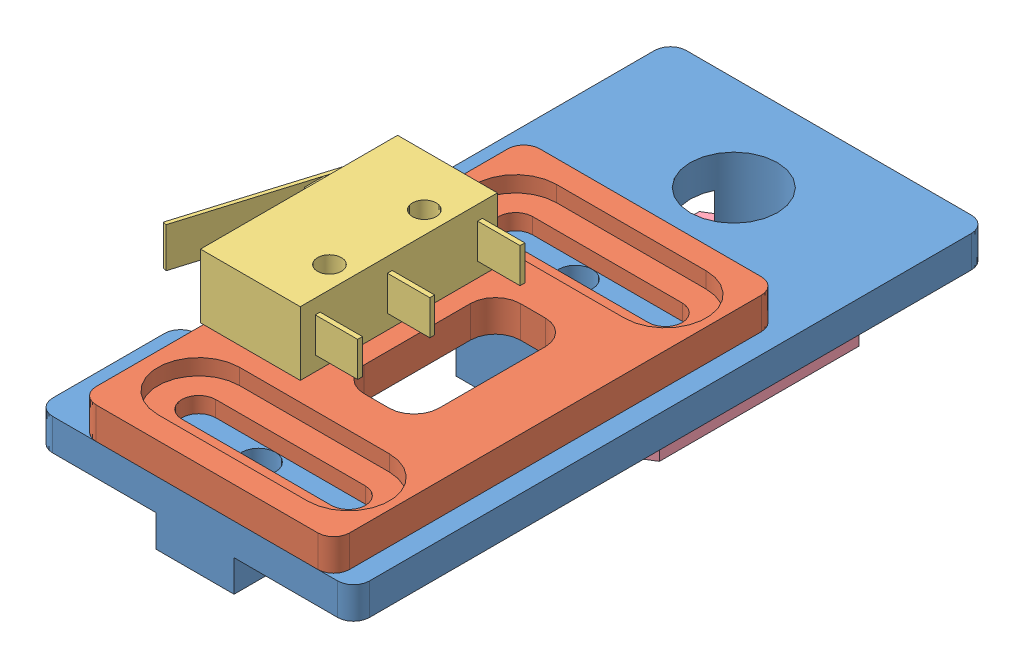
SolidWorks assembly Frame Carriage Endstop Assembly RH, configuration Default. Lengths in mm.
Overall size (33.09 22.27 63.5).
5 component instances, 5 part files, 15 mates.
Components (placement in the parent):
- Carriage Axis Endstop Mount Base RH-1: Carriage Axis Endstop Mount Base RH [Default] at (-146.9546 69.2713 -55.6911) size (31.75 6.35 63.5)
- Carriage Axis Endstop Mount Slide RH-1: Carriage Axis Endstop Mount Slide RH [Default] at (-148.9445 72.4463 7.8089) size (25.4 3.17 44.45)
- Endstop-4: Endstop [Default] at (-164.6445 75.6213 -4.5411) x (0 0 -1) z (1 0 0) size (19.75 6.4 19.65)
- 5_16in T-Slot Nut-1: 5_16in T-Slot Nut [Default] at (-170.8296 60.4163 -50.7161) x (0 0 1) z (-1 0 0) size (25 5.68 16)
- 5_16in x 0.5in T-Slot Bolt-1: 5_16in x 0.5in T-Slot Bolt [Default] at (-162.8296 59.7463 -46.1661) x (0 0 -1) z (1 0 0) size (16.95 16.6 16.95)
Mates (geometry in assembly coordinates):
- Tangent2: tangent: cylinder of ? through (16.9117 26.5861 68.4807) axis (0 1 0) radius 1.7; plane of ? through (9.8098 36.1111 66.7807) normal (0 0 1)
- Coincident1: coincident: plane of ? through (1.0367 32.9361 74.8307) normal (0 1 0); plane of ? through (4.9348 32.9361 74.8307) normal (0 -1 0)
- Coincident2: coincident: plane of ? through (1.0367 29.7611 74.8307) normal (0 0 1); plane of ? through (4.9348 36.1111 74.8307) normal (0 0 1)
- Coincident3: coincident: plane of ? through (4.9348 36.1111 74.8307) normal (0 1 0); plane of ? through (20.6348 36.1111 62.4807) normal (0 -1 0)
- Concentric1: concentric: cylinder of ? through (22.8348 36.1111 57.3557) axis (0 -1 0) radius 1.2; cylinder of ? through (22.8348 36.1111 57.3557) axis (0 1 0) radius 1.2
- Coincident5: coincident: plane of Carriage Axis Endstop Mount Slide RH-1 through (-148.9445 75.6213 7.8089) normal (0 1 0); plane of Endstop-4 through (-164.6445 75.6213 -4.5411) normal (0 -1 0)
- Concentric2: concentric: cylinder of Carriage Axis Endstop Mount Slide RH-1 through (-166.8445 75.6213 -19.1661) axis (0 -1 0) radius 1.2; cylinder of Endstop-4 through (-166.8445 82.0213 -19.1661) axis (0 -1 0) radius 1.2
- Concentric3: concentric: cylinder of Carriage Axis Endstop Mount Slide RH-1 through (-166.8445 75.6213 -9.6661) axis (0 -1 0) radius 1.2; cylinder of Endstop-4 through (-166.8445 82.0213 -9.6661) axis (0 -1 0) radius 1.2
- Concentric4: concentric: cylinder of Carriage Axis Endstop Mount Base RH-1 through (-162.8296 66.0963 -46.1661) axis (0 1 0) radius 4.3656; cylinder of ? through (-162.8296 72.4463 -46.1661) axis (0 -1 0) radius 3.9688
- Coincident6: coincident: plane of Carriage Axis Endstop Mount Base RH-1 through (-146.9546 72.4463 7.8089) normal (0 1 0); plane of ? through (-162.8296 72.4463 -46.1661) normal (0 -1 0)
- Concentric5: concentric: cylinder of ? through (-162.8296 72.4463 -46.1661) axis (0 -1 0) radius 3.9688; cylinder of 5_16in T-Slot Nut-1 through (-162.8296 64.0963 -46.1661) axis (0 -1 0) radius 3.9688
- Coincident8: coincident: plane of Carriage Axis Endstop Mount Base RH-1 through (-146.9546 66.0963 7.8089) normal (0 -1 0); plane of 5_16in T-Slot Nut-1 through (-162.8296 66.0963 -46.1661) normal (0 1 0)
- Parallel1: parallel: plane of Carriage Axis Endstop Mount Base RH-1 through (-178.7046 69.2713 7.8089) normal (-1 0 0); plane of 5_16in T-Slot Nut-1 through (-154.8296 64.0963 -50.7161) normal (1 0 0)
- Concentric6: concentric: cylinder of Carriage Axis Endstop Mount Base RH-1 through (-162.8296 66.0963 -46.1661) axis (0 1 0) radius 4.3656; cylinder of 5_16in x 0.5in T-Slot Bolt-1 through (-162.8296 72.4463 -46.1661) axis (0 -1 0) radius 3.9688
- Coincident9: coincident: plane of Carriage Axis Endstop Mount Base RH-1 through (-146.9546 72.4463 7.8089) normal (0 1 0); plane of 5_16in x 0.5in T-Slot Bolt-1 through (-162.8296 72.4463 -46.1661) normal (0 -1 0)
